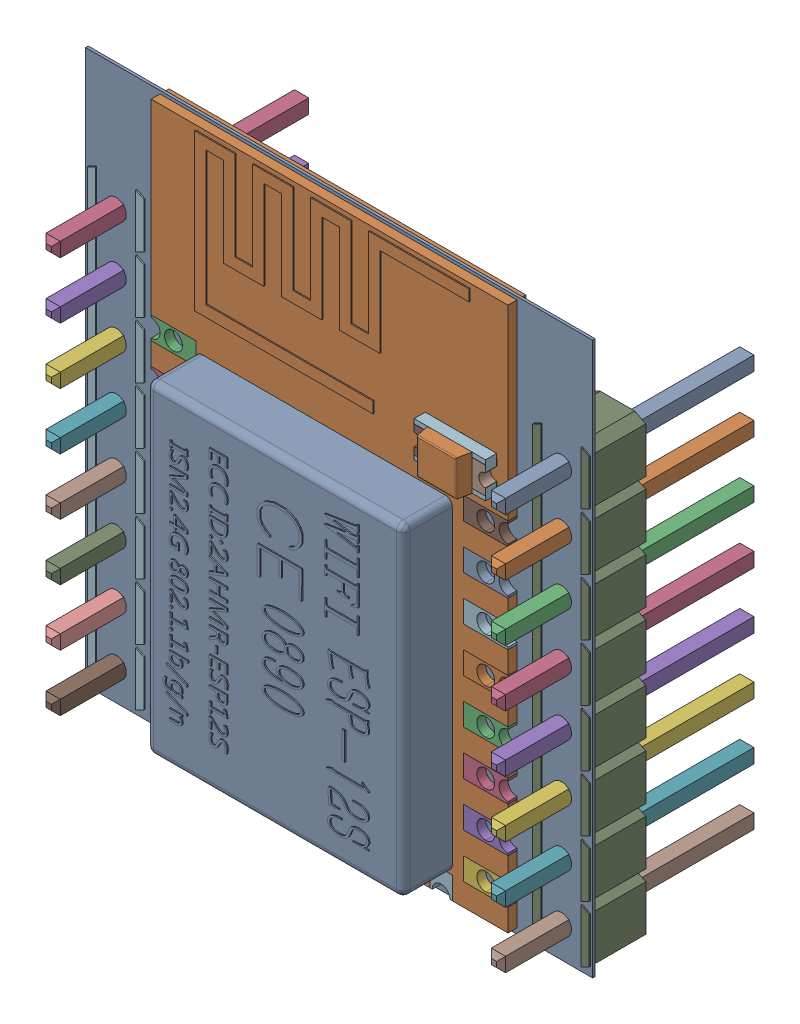
SolidWorks assembly ESP-12S, configuration ﾃﾞﾌｫﾙﾄ. Lengths in mm.
Overall size (22.73 24.76 11.54).
51 component instances, 25 part files, 0 mates.
Components (placement in the parent):
- PCB-1-1: PCB-1 [ﾃﾞﾌｫﾙﾄ] at (0 0 9.144) size (22.73 24.76 11.54)
  - Board-1-1: Board-1 [ﾃﾞﾌｫﾙﾄ] at origin size (22.73 24.76 0.12)
    - Open CASCADE STEP translator 6.8 1.1.1-1: Open CASCADE STEP translator 6.8 1.1.1 [ﾃﾞﾌｫﾙﾄ] at (0 0 -0.1168) size (22.73 24.76 0.12)
  - P3-1: P3 [ﾃﾞﾌｫﾙﾄ] at origin size (16 24.38 3.05)
    - 0411-2-1: 0411-2 [ﾃﾞﾌｫﾙﾄ] at (11.34 12.4403 0) x (0 1 0) z (-1 0 0) size (24.38 3.05 16)
      - User_Library-ESP8266-12E_PCB1-1: User_Library-ESP8266-12E_PCB1 [ﾃﾞﾌｫﾙﾄ] x (-1 0 0) z (0 0 1) size (24.38 0.8 16)
      - User_Library-ESP8266-12E_Pin1-1: User_Library-ESP8266-12E_Pin1 [ﾃﾞﾌｫﾙﾄ] at (3.31 0 8) x (-1 0 0) z (0 -1 0) size (1 2 0.8)
      - User_Library-ESP8266-12E_Pin1-2: User_Library-ESP8266-12E_Pin1 [ﾃﾞﾌｫﾙﾄ] at (1.31 0 8) x (-1 0 0) z (0 -1 0) size (1 2 0.8)
      - User_Library-ESP8266-12E_Pin1-3: User_Library-ESP8266-12E_Pin1 [ﾃﾞﾌｫﾙﾄ] at (-0.69 0 8) x (-1 0 0) z (0 -1 0) size (1 2 0.8)
      - User_Library-ESP8266-12E_Pin1-4: User_Library-ESP8266-12E_Pin1 [ﾃﾞﾌｫﾙﾄ] at (-2.69 0 8) x (-1 0 0) z (0 -1 0) size (1 2 0.8)
      - User_Library-ESP8266-12E_Pin1-5: User_Library-ESP8266-12E_Pin1 [ﾃﾞﾌｫﾙﾄ] at (-4.69 0 8) x (-1 0 0) z (0 -1 0) size (1 2 0.8)
      - User_Library-ESP8266-12E_Pin1-6: User_Library-ESP8266-12E_Pin1 [ﾃﾞﾌｫﾙﾄ] at (-6.69 0 8) x (-1 0 0) z (0 -1 0) size (1 2 0.8)
      - User_Library-ESP8266-12E_Pin1-7: User_Library-ESP8266-12E_Pin1 [ﾃﾞﾌｫﾙﾄ] at (-8.69 0 8) x (-1 0 0) z (0 -1 0) size (1 2 0.8)
      - User_Library-ESP8266-12E_Pin1-8: User_Library-ESP8266-12E_Pin1 [ﾃﾞﾌｫﾙﾄ] at (-10.69 0 8) x (-1 0 0) z (0 -1 0) size (1 2 0.8)
      - User_Library-ESP8266-12E_Pin1-9: User_Library-ESP8266-12E_Pin1 [ﾃﾞﾌｫﾙﾄ] at (3.31 0 -8) x (1 0 0) z (0 -1 0) size (1 2 0.8)
      - User_Library-ESP8266-12E_Pin1-10: User_Library-ESP8266-12E_Pin1 [ﾃﾞﾌｫﾙﾄ] at (-0.69 0 -8) x (1 0 0) z (0 -1 0) size (1 2 0.8)
      - User_Library-ESP8266-12E_Pin1-11: User_Library-ESP8266-12E_Pin1 [ﾃﾞﾌｫﾙﾄ] at (1.31 0 -8) x (1 0 0) z (0 -1 0) size (1 2 0.8)
      - User_Library-ESP8266-12E_Pin1-12: User_Library-ESP8266-12E_Pin1 [ﾃﾞﾌｫﾙﾄ] at (-2.69 0 -8) x (1 0 0) z (0 -1 0) size (1 2 0.8)
      - User_Library-ESP8266-12E_Pin1-13: User_Library-ESP8266-12E_Pin1 [ﾃﾞﾌｫﾙﾄ] at (-4.69 0 -8) x (1 0 0) z (0 -1 0) size (1 2 0.8)
      - User_Library-ESP8266-12E_Pin1-14: User_Library-ESP8266-12E_Pin1 [ﾃﾞﾌｫﾙﾄ] at (-6.69 0 -8) x (1 0 0) z (0 -1 0) size (1 2 0.8)
      - User_Library-ESP8266-12E_Pin1-15: User_Library-ESP8266-12E_Pin1 [ﾃﾞﾌｫﾙﾄ] at (-8.69 0 -8) x (1 0 0) z (0 -1 0) size (1 2 0.8)
      - User_Library-ESP8266-12E_Pin1-16: User_Library-ESP8266-12E_Pin1 [ﾃﾞﾌｫﾙﾄ] at (-10.69 0 -8) x (1 0 0) z (0 -1 0) size (1 2 0.8)
      - User_Library-ESP8266-12E_Pin2-1: User_Library-ESP8266-12E_Pin2 [ﾃﾞﾌｫﾙﾄ] at (-12.19 0 5) x (0 0 1) z (0 1 0) size (1 1 0.8)
      - User_Library-ESP8266-12E_Pin2-2: User_Library-ESP8266-12E_Pin2 [ﾃﾞﾌｫﾙﾄ] at (-12.19 0 3) x (0 0 -1) z (0 -1 0) size (1 1 0.8)
      - User_Library-ESP8266-12E_Pin2-3: User_Library-ESP8266-12E_Pin2 [ﾃﾞﾌｫﾙﾄ] at (-12.19 0 1) x (0 0 1) z (0 1 0) size (1 1 0.8)
      - User_Library-ESP8266-12E_Pin2-4: User_Library-ESP8266-12E_Pin2 [ﾃﾞﾌｫﾙﾄ] at (-12.19 0 -1) x (0 0 1) z (0 1 0) size (1 1 0.8)
      - User_Library-ESP8266-12E_Pin2-5: User_Library-ESP8266-12E_Pin2 [ﾃﾞﾌｫﾙﾄ] at (-12.19 0 -3) x (0 0 1) z (0 1 0) size (1 1 0.8)
      - User_Library-ESP8266-12E_Pin2-6: User_Library-ESP8266-12E_Pin2 [ﾃﾞﾌｫﾙﾄ] at (-12.19 0 -5) x (0 0 1) z (0 1 0) size (1 1 0.8)
      - User_Library-ESP8266-12E_Lid-1: User_Library-ESP8266-12E_Lid [ﾃﾞﾌｫﾙﾄ] at (-3.84 -1.5 0.25) x (0 0 -1) z (0 -1 0) size (11.5 14.5 2.25)
      - User_Library-ESP8266-12E_Antenne-1: User_Library-ESP8266-12E_Antenne [ﾃﾞﾌｫﾙﾄ] at (4.99 -0.425 6) x (0 0 -1) z (0 -1 0) size (12.3 7 0.05)
      - User_Library-ESP8266-12E_Surface_Mount_Chip_LED_3.2x1.6mm-1: User_Library-ESP8266-12E_Surface_Mount_Chip_LED_3.2x1.6mm [ﾃﾞﾌｫﾙﾄ] at (6.19 -0.41 -7.5) x (0 0 1) z (0 -1 0) size (3.2 1.6 1.13)
  - Open CASCADE STEP translator 6.8 1.3-1: Open CASCADE STEP translator 6.8 1.3 [ﾃﾞﾌｫﾙﾄ] at origin size (2.54 20.32 11.54)
    - Header8_2.54mm-1: Header8_2.54mm [ﾃﾞﾌｫﾙﾄ] at (1.3969 10.3123 -1.2168) x (0 -1 0) z (1 0 0) size (0.64 11.54 0.64)
    - Header8_2.54mm-2-1: Header8_2.54mm-2 [ﾃﾞﾌｫﾙﾄ] at (1.3969 10.3123 -1.2168) x (0 -1 0) z (1 0 0) size (0.64 11.54 0.64)
    - Header8_2.54mm-3-1: Header8_2.54mm-3 [ﾃﾞﾌｫﾙﾄ] at (1.3969 10.3123 -1.2168) x (0 -1 0) z (1 0 0) size (0.64 11.54 0.64)
    - Header8_2.54mm-4-1: Header8_2.54mm-4 [ﾃﾞﾌｫﾙﾄ] at (1.3969 10.3123 -1.2168) x (0 -1 0) z (1 0 0) size (0.64 11.54 0.64)
    - Header8_2.54mm-5-1: Header8_2.54mm-5 [ﾃﾞﾌｫﾙﾄ] at (1.3969 10.3123 -1.2168) x (0 -1 0) z (1 0 0) size (0.64 11.54 0.64)
    - Header8_2.54mm-6-1: Header8_2.54mm-6 [ﾃﾞﾌｫﾙﾄ] at (1.3969 10.3123 -1.2168) x (0 -1 0) z (1 0 0) size (0.64 11.54 0.64)
    - Header8_2.54mm-7-1: Header8_2.54mm-7 [ﾃﾞﾌｫﾙﾄ] at (1.3969 10.3123 -1.2168) x (0 -1 0) z (1 0 0) size (0.64 11.54 0.64)
    - Header8_2.54mm-8-1: Header8_2.54mm-8 [ﾃﾞﾌｫﾙﾄ] at (1.3969 10.3123 -1.2168) x (0 -1 0) z (1 0 0) size (0.64 11.54 0.64)
    - Header8_2.54mm-9-1: Header8_2.54mm-9 [ﾃﾞﾌｫﾙﾄ] at (1.3969 10.3123 -1.2168) x (0 -1 0) z (1 0 0) size (20.32 2.54 2.54)
  - 1-10-1: 1-10 [ﾃﾞﾌｫﾙﾄ] at origin size (2.54 20.32 11.54)
    - Header8_2.54mm_RGB255-1: Header8_2.54mm_RGB255 [ﾃﾞﾌｫﾙﾄ] at (21.3613 10.3123 -1.2168) x (0 -1 0) z (1 0 0) size (0.64 11.54 0.64)
    - Header8_2.54mm_RGB255-11-1: Header8_2.54mm_RGB255-11 [ﾃﾞﾌｫﾙﾄ] at (21.3613 10.3123 -1.2168) x (0 -1 0) z (1 0 0) size (0.64 11.54 0.64)
    - Header8_2.54mm_RGB255-12-1: Header8_2.54mm_RGB255-12 [ﾃﾞﾌｫﾙﾄ] at (21.3613 10.3123 -1.2168) x (0 -1 0) z (1 0 0) size (0.64 11.54 0.64)
    - Header8_2.54mm_RGB255-13-1: Header8_2.54mm_RGB255-13 [ﾃﾞﾌｫﾙﾄ] at (21.3613 10.3123 -1.2168) x (0 -1 0) z (1 0 0) size (0.64 11.54 0.64)
    - Header8_2.54mm_RGB255-14-1: Header8_2.54mm_RGB255-14 [ﾃﾞﾌｫﾙﾄ] at (21.3613 10.3123 -1.2168) x (0 -1 0) z (1 0 0) size (0.64 11.54 0.64)
    - Header8_2.54mm_RGB255-15-1: Header8_2.54mm_RGB255-15 [ﾃﾞﾌｫﾙﾄ] at (21.3613 10.3123 -1.2168) x (0 -1 0) z (1 0 0) size (0.64 11.54 0.64)
    - Header8_2.54mm_RGB255-16-1: Header8_2.54mm_RGB255-16 [ﾃﾞﾌｫﾙﾄ] at (21.3613 10.3123 -1.2168) x (0 -1 0) z (1 0 0) size (0.64 11.54 0.64)
    - Header8_2.54mm_RGB255-17-1: Header8_2.54mm_RGB255-17 [ﾃﾞﾌｫﾙﾄ] at (21.3613 10.3123 -1.2168) x (0 -1 0) z (1 0 0) size (0.64 11.54 0.64)
    - Header8_2.54mm_RGB255-18-1: Header8_2.54mm_RGB255-18 [ﾃﾞﾌｫﾙﾄ] at (21.3613 10.3123 -1.2168) x (0 -1 0) z (1 0 0) size (20.32 2.54 2.54)
